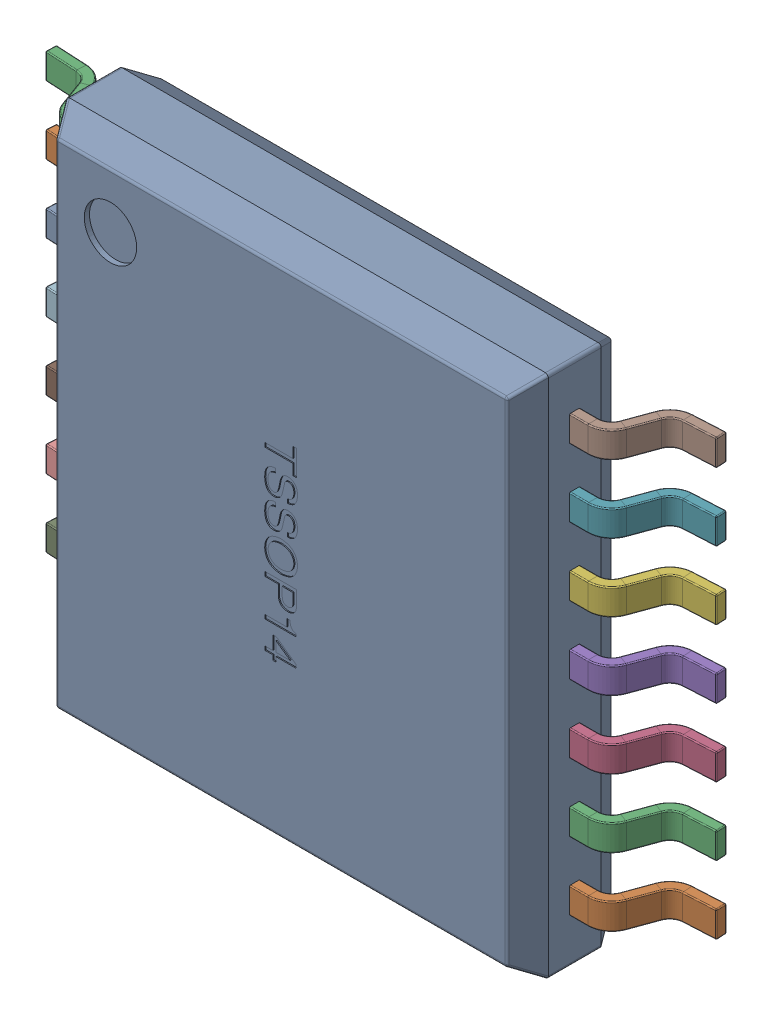
SolidWorks assembly TSSOP14, configuration Default. Lengths in mm.
Overall size (6.4 5 1.05).
16 component instances, 3 part files, 0 mates.
Components (placement in the parent):
- TSSOP14__X_CB_X_DC_X_CC_X_E5-1: TSSOP14__X_CB_X_DC_X_CC_X_E5 [Default] at origin size (4.6 5 1)
- _X_D2_X_FD_X_BD_X_C5_0.9-1: _X_D2_X_FD_X_BD_X_C5_0.9 [Default] at (2.3 -1.95 0.53) x (0 1 0) z (0 0 1) size (0.25 0.9 0.6)
- _X_D2_X_FD_X_BD_X_C5_0.9-2: _X_D2_X_FD_X_BD_X_C5_0.9 [Default] at (2.3 -1.3 0.53) x (0 1 0) z (0 0 1) size (0.25 0.9 0.6)
- _X_D2_X_FD_X_BD_X_C5_0.9-3: _X_D2_X_FD_X_BD_X_C5_0.9 [Default] at (2.3 -0.65 0.53) x (0 1 0) z (0 0 1) size (0.25 0.9 0.6)
- _X_D2_X_FD_X_BD_X_C5_0.9-4: _X_D2_X_FD_X_BD_X_C5_0.9 [Default] at (2.3 0 0.53) x (0 1 0) z (0 0 1) size (0.25 0.9 0.6)
- _X_D2_X_FD_X_BD_X_C5_0.9-5: _X_D2_X_FD_X_BD_X_C5_0.9 [Default] at (2.3 0.65 0.53) x (0 1 0) z (0 0 1) size (0.25 0.9 0.6)
- _X_D2_X_FD_X_BD_X_C5_0.9-6: _X_D2_X_FD_X_BD_X_C5_0.9 [Default] at (2.3 1.3 0.53) x (0 1 0) z (0 0 1) size (0.25 0.9 0.6)
- _X_D2_X_FD_X_BD_X_C5_0.9-7: _X_D2_X_FD_X_BD_X_C5_0.9 [Default] at (2.3 1.95 0.53) x (0 1 0) z (0 0 1) size (0.25 0.9 0.6)
- _X_D2_X_FD_X_BD_X_C5_0.9-8: _X_D2_X_FD_X_BD_X_C5_0.9 [Default] at (-2.3 -1.95 0.53) x (0 -1 0) z (0 0 1) size (0.25 0.9 0.6)
- _X_D2_X_FD_X_BD_X_C5_0.9-9: _X_D2_X_FD_X_BD_X_C5_0.9 [Default] at (-2.3 -1.3 0.53) x (0 -1 0) z (0 0 1) size (0.25 0.9 0.6)
- _X_D2_X_FD_X_BD_X_C5_0.9-10: _X_D2_X_FD_X_BD_X_C5_0.9 [Default] at (-2.3 -0.65 0.53) x (0 -1 0) z (0 0 1) size (0.25 0.9 0.6)
- _X_D2_X_FD_X_BD_X_C5_0.9-11: _X_D2_X_FD_X_BD_X_C5_0.9 [Default] at (-2.3 0 0.53) x (0 -1 0) z (0 0 1) size (0.25 0.9 0.6)
- _X_D2_X_FD_X_BD_X_C5_0.9-12: _X_D2_X_FD_X_BD_X_C5_0.9 [Default] at (-2.3 0.65 0.53) x (0 -1 0) z (0 0 1) size (0.25 0.9 0.6)
- _X_D2_X_FD_X_BD_X_C5_0.9-13: _X_D2_X_FD_X_BD_X_C5_0.9 [Default] at (-2.3 1.3 0.53) x (0 -1 0) z (0 0 1) size (0.25 0.9 0.6)
- _X_D2_X_FD_X_BD_X_C5_0.9-14: _X_D2_X_FD_X_BD_X_C5_0.9 [Default] at (-2.3 1.95 0.53) x (0 -1 0) z (0 0 1) size (0.25 0.9 0.6)
- LOGOԲ0.25-1: LOGOԲ0.25 [Default] at (0.0665 0.0379 0.025) size (0.75 0.87 0.01)
